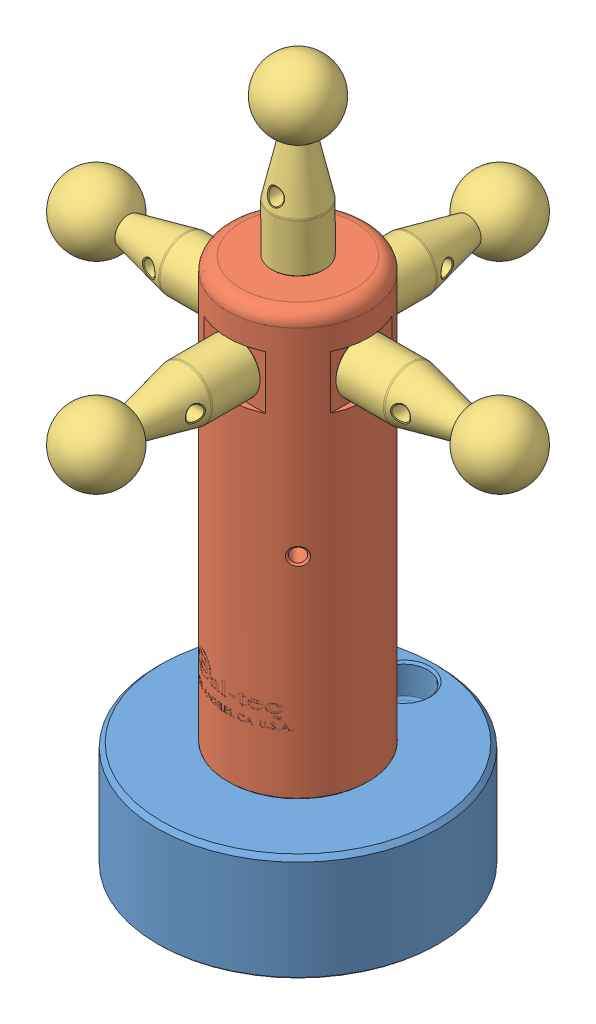
SolidWorks assembly PM-STAR-75, configuration Default. Lengths in mm.
Overall size (171.2 253.24 171.2).
7 component instances, 3 part files, 9 mates.
Components (placement in the parent):
- PLT-4 - Four Inch Universal Platform-1: PLT-4 - Four Inch Universal Platform [Default] at origin size (101.6 38.1 101.6)
- Tree Probe Trunk-1: Tree Probe Trunk [Default] at (0 38.1 0) size (50.8 152.4 50.8)
- calibration sphere 1 inch-1: calibration sphere 1 inch [Default] at (-22.86 167.767 0) x (0 1 0) z (0 0 1) size (25.4 62.74 25.4)
- calibration sphere 1 inch-2: calibration sphere 1 inch [Default] at (0 190.5 0) size (25.4 62.74 25.4)
- calibration sphere 1 inch-3: calibration sphere 1 inch [Default] at (0 167.767 -22.86) x (0 1 0) z (-1 0 0) size (25.4 62.74 25.4)
- calibration sphere 1 inch-4: calibration sphere 1 inch [Default] at (22.86 167.767 0) x (0 1 0) z (0 0 -1) size (25.4 62.74 25.4)
- calibration sphere 1 inch-5: calibration sphere 1 inch [Default] at (0 167.767 22.86) x (0 1 0) z (1 0 0) size (25.4 62.74 25.4)
Mates (geometry in assembly coordinates):
- Coincident1: coincident anti-aligned: plane of PLT-4 - Four Inch Universal Platform-1 through (50.8 38.1 0) normal (0 1 0); plane of Tree Probe Trunk-1 through (0 38.1 0) normal (0 -1 0)
- Concentric1: concentric anti-aligned: cylinder of PLT-4 - Four Inch Universal Platform-1; cylinder of Tree Probe Trunk-1
- Coincident2: coincident aligned: plane of PLT-4 - Four Inch Universal Platform-1 through (0 0 0) normal (0 0 1); plane of Tree Probe Trunk-1 through (0 38.1 0) normal (0 0 1)
- Coincident3: coincident anti-aligned: plane of Tree Probe Trunk-1 through (-22.86 158.115 -25.4) normal (-1 0 0); plane of calibration sphere 1 inch-1 through (-22.86 167.767 0) normal (1 0 0)
- Concentric2: concentric anti-aligned: cylinder of Tree Probe Trunk-1; cylinder of calibration sphere 1 inch-1
- Coincident4: coincident anti-aligned: plane of Tree Probe Trunk-1 through (0 190.5 0) normal (0 1 0); plane of calibration sphere 1 inch-2 through (0 190.5 0) normal (0 -1 0)
- Concentric3: concentric anti-aligned: cylinder of Tree Probe Trunk-1; cylinder of calibration sphere 1 inch-2
- Parallel1: parallel aligned: plane of calibration sphere 1 inch-1 through (-22.86 167.767 0) normal (0 0 1); plane of assembly
- Parallel2: parallel aligned: plane of calibration sphere 1 inch-2 through (0 190.5 0) normal (0 0 1); plane of assembly
